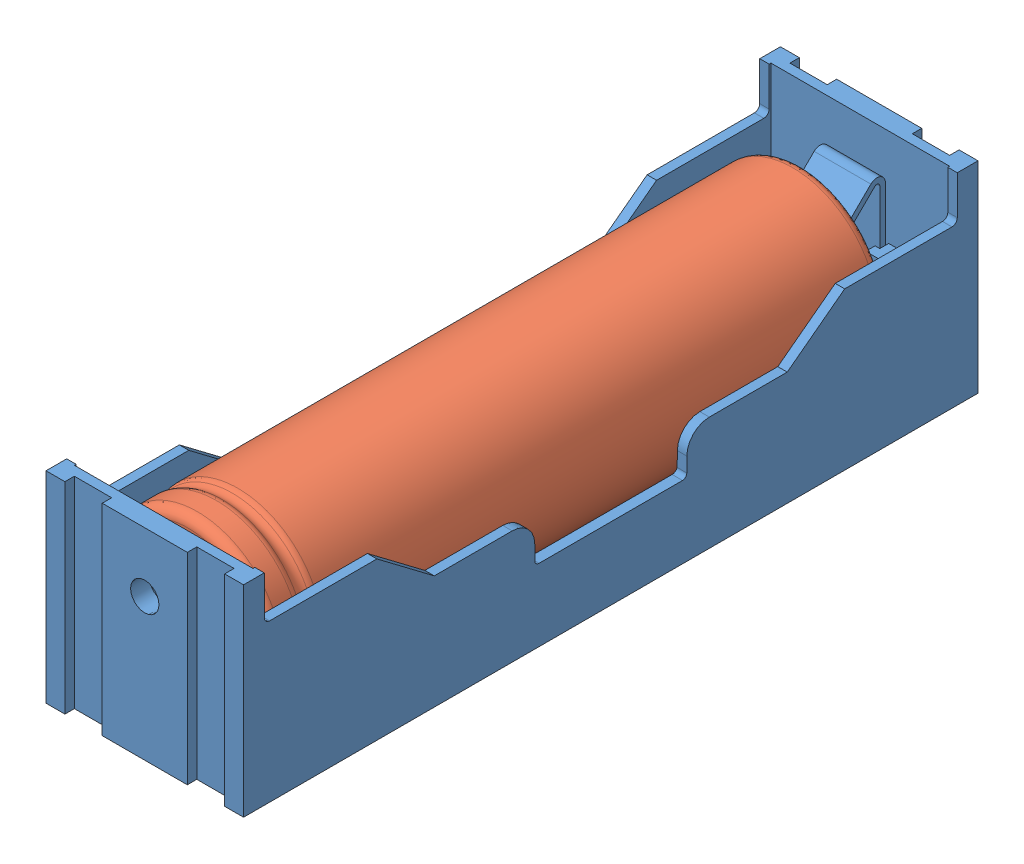
SolidWorks assembly battery_assembly, configuration Predeterminado. Lengths in mm.
Overall size (20.9 21.4 77.7).
2 component instances, 2 part files, 3 mates.
Components (placement in the parent):
- Li-Ion_Cell_Holder_BH_18650_A-1: Li-Ion_Cell_Holder_BH_18650_A [Default] at (-4.0971 -15.8723 77.7) size (20.9 21.4 77.7)
- АКБ 18650-1: АКБ 18650 [По умолчанию] at (-4.0971 -4.8723 46.9822) size (18 18 65.07)
Mates (geometry in assembly coordinates):
- Coincidente1: coincident: plane of АКБ 18650-1 through (2.561 -4.8723 47.0822) normal (0 0 -1); plane of Li-Ion_Cell_Holder_BH_18650_A-1 through (-1.0971 -3.3129 47.0822) normal (0 0 1)
- Tangente1: tangent: plane of Li-Ion_Cell_Holder_BH_18650_A-1 through (-4.0971 -13.8723 77.7) normal (0 1 0); cylinder of АКБ 18650-1 through (2.561 -4.8723 111.9822) axis (0 0 -1) radius 9
- Coincidente2: coincident aligned: plane of Li-Ion_Cell_Holder_BH_18650_A-1 through (-4.0971 -15.8723 77.7) normal (1 0 0); plane of АКБ 18650-1 through (-4.0971 -4.8723 46.9822) normal (1 0 0)
